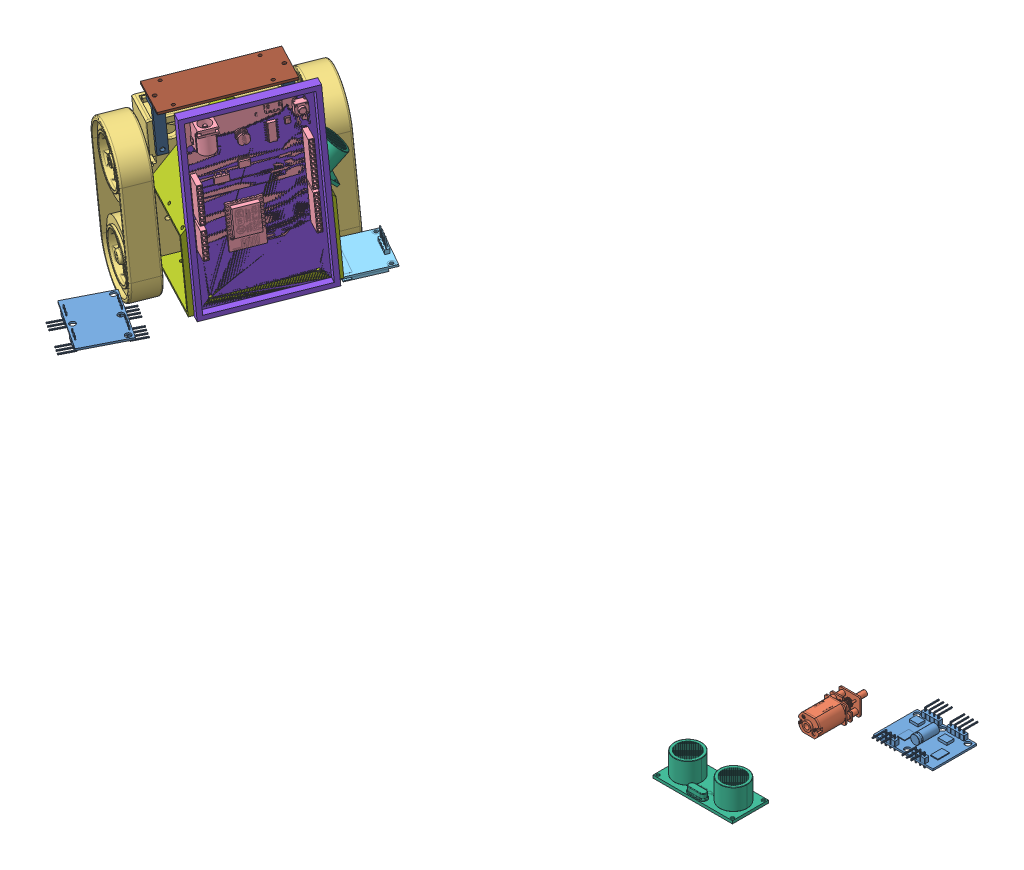
SolidWorks assembly ENGR122_Project, configuration Default. Lengths in mm.
Overall size (434.37 208.02 155.91).
15 component instances, 11 part files, 25 mates.
Components (placement in the parent):
- ENGR122_FeeTech-SMC-4CH-1: ENGR122_FeeTech-SMC-4CH [Default] at (-40.4748 33.8724 47.1125) size (34 8 38)
- ENGR122_DCmotorWgear-1: ENGR122_DCmotorWgear [Default] at (-74.293 41.035 64.7504) size (12.04 10 33.4)
- ENGR122_ZumoChassis-1: ENGR122_ZumoChassis [Default] at (-483.3326 204.8387 50.8004) x (0.037202 -0.996773 -0.071124) z (-0.461988 -0.080266 0.883246) size (87.2 39 99)
- ENGR122_WeMosD1-1: ENGR122_WeMosD1 [Default] at (-388.9016 203.5007 122.9705) x (0.037202 -0.996773 -0.071124) z (0.886105 0 0.463484) size (70.96 53.34 14.5)
- ENGR122_OLED_Display-1: ENGR122_OLED_Display [Default] at (-392.5335 112.0503 26.5045) x (-0.870853 0.002571 -0.491536) z (0.037202 -0.996773 -0.071124) size (26.7 27.86 10.85)
- ENGR122_HCSR04-1: ENGR122_HCSR04 [Default] at (-92.8271 8.0658 62.7388) size (45.31 20.38 60.51)
- ENGR122_Body-1: ENGR122_Body [Default] at (-403.7579 159.6083 60.9495) x (-0.037202 0.996773 0.071124) z (0.461988 0.080266 -0.883246) size (76.2 41.91 66.04)
- ENGR122_Hat-4: ENGR122_Hat [Default] at (-372.2641 143.0258 88.4223) x (0.037202 -0.996773 -0.071124) z (-0.461988 -0.080266 0.883246) size (101.6 5.08 60.96)
- ENGR112_ConnectorA-2: ENGR112_ConnectorA [Default] at (-392.5958 91.7918 104.0934) x (0.037202 -0.996773 -0.071124) z (-0.461988 -0.080266 0.883246) size (12.7 8.89 5.08)
- ENGR112_ConnectorA-3: ENGR112_ConnectorA [Default] at (-369.4931 95.8057 59.9249) x (0.037202 -0.996773 -0.071124) z (-0.461988 -0.080266 0.883246) size (12.7 8.89 5.08)
- ENGR122_HCSR04-2: ENGR122_HCSR04 [Default] at (-413.485 165.1149 47.6247) x (0.343228 -0.672012 -0.656196) z (0.886105 0 0.463484) size (45.31 20.38 60.51)
- ENGR112_ConnectorB-2: ENGR112_ConnectorB [Default] at (-391.4138 239.8096 64.4747) x (-0.037202 0.996773 0.071124) z (0.461988 0.080266 -0.883246) size (25.4 8.89 5.08)
- ENGR112_ConnectorB-3: ENGR112_ConnectorB [Default] at (-416.8231 235.395 113.0532) x (-0.037202 0.996773 0.071124) z (0.461988 0.080266 -0.883246) size (25.4 8.89 5.08)
- ENGR122_Front-1: ENGR122_Front [Default] at (-414.0474 189.9129 59.4508) x (0.461988 0.080266 -0.883246) z (0.037202 -0.996773 -0.071124) size (60.07 22.86 1.27)
- ENGR122_FeeTech-SMC-4CH-2: ENGR122_FeeTech-SMC-4CH [Default] at (-415.5041 103.983 145.0533) x (-0.837314 0.007757 -0.546668) z (-0.545456 -0.079891 0.834323) size (34 8 38)
Mates (geometry in assembly coordinates):
- Coincident5: coincident anti-aligned: plane of ENGR122_ZumoChassis-1 through (-426.2035 174.0605 103.8617) normal (0.886105 0 0.463484); plane of ENGR122_Body-1 through (-403.7667 159.8441 60.9663) normal (-0.886105 0 -0.463484)
- Coincident9: coincident: line of ENGR122_ZumoChassis-1 through (-394.627 121.3557 43.4926) axis (-0.037202 0.996773 0.071124); plane of ENGR122_Body-1 through (-357.1525 112.305 62.2714) normal (0.461988 0.080266 -0.883246)
- Coincident19: coincident aligned: circle of ENGR122_Body-1; cylinder of ENGR122_Hat-4 through (-393.3569 114.7934 106.8272) axis (0.886105 0 0.463484) radius 1.016
- Coincident20: coincident anti-aligned: plane of ENGR122_Body-1 through (-387.6622 107.0042 120.601) normal (0.037202 -0.996773 -0.071124); plane of ENGR112_ConnectorA-2 through (-414.1495 107.4858 99.9973) normal (-0.037202 0.996773 0.071124)
- Coincident21: coincident anti-aligned: plane of ENGR122_ZumoChassis-1 through (-426.2035 174.0605 103.8617) normal (0.886105 0 0.463484); plane of ENGR112_ConnectorA-2 through (-422.027 107.4858 95.8769) normal (-0.886105 0 -0.463484)
- Concentric3: concentric aligned: circle of ENGR122_ZumoChassis-1; circle of ENGR112_ConnectorA-2
- Coincident22: coincident anti-aligned: plane of ENGR122_Body-1 through (-387.6622 107.0042 120.601) normal (0.037202 -0.996773 -0.071124); plane of ENGR112_ConnectorA-3 through (-391.0468 111.4997 55.8288) normal (-0.037202 0.996773 0.071124)
- Coincident23: coincident anti-aligned: plane of ENGR122_ZumoChassis-1 through (-426.2035 174.0605 103.8617) normal (0.886105 0 0.463484); plane of ENGR112_ConnectorA-3 through (-398.9243 111.4997 51.7084) normal (-0.886105 0 -0.463484)
- Coincident25: coincident anti-aligned: plane of ENGR122_Body-1 through (-358.678 153.1774 65.1879) normal (0.311467 0.74054 -0.595474); plane of ENGR122_HCSR04-2 through (-377.0137 178.4162 86.9845) normal (-0.311467 -0.74054 0.595474)
- Parallel5: parallel anti-aligned: line of ENGR122_Body-1 through (-375.2422 185.6087 96.8559) axis (-0.886105 0 -0.463484); line of ENGR122_HCSR04-2 through (-393.0014 187.4371 84.0973) axis (0.886105 0 0.463484)
- Concentric9: concentric anti-aligned: circle of ENGR122_Body-1; circle of ENGR122_HCSR04-2
- Concentric10: concentric anti-aligned: cylinder of ENGR122_Body-1 through (-392.4359 120.0585 53.0043) axis (0.037202 -0.996773 -0.071124) radius 1.016; cylinder of ENGR112_ConnectorA-3 through (-392.0296 109.1717 52.2275) axis (-0.037202 0.996773 0.071124) radius 1.016
- Coincident35: coincident aligned: plane of ENGR122_WeMosD1-1 through (-375.3988 172.3823 97.1554) normal (0.886105 0 0.463484); plane of ENGR122_Hat-4 through (-371.1476 143.2615 89.0277) normal (0.886105 0 0.463484)
- Coincident36: coincident anti-aligned: plane of ENGR122_WeMosD1-1 through (-386.4536 137.9095 118.2903) normal (-0.461988 -0.080266 0.883246); plane of ENGR122_Hat-4 through (-388.9774 205.5306 123.1154) normal (0.461988 0.080266 -0.883246)
- Coincident37: coincident anti-aligned: plane of ENGR122_WeMosD1-1 through (-383.2949 206.5179 112.2514) normal (-0.037202 0.996773 0.071124); plane of ENGR122_Hat-4 through (-363.1614 210.0159 73.7596) normal (0.037202 -0.996773 -0.071124)
- Coincident42: coincident anti-aligned: plane of ENGR122_ZumoChassis-1 through (-426.2035 174.0605 103.8617) normal (0.886105 0 0.463484); plane of ENGR112_ConnectorB-2 through (-398.2419 187.5633 50.4037) normal (-0.886105 0 -0.463484)
- Coincident44: coincident anti-aligned: plane of ENGR122_ZumoChassis-1 through (-426.2035 174.0605 103.8617) normal (0.886105 0 0.463484); plane of ENGR112_ConnectorB-3 through (-423.6512 183.1486 98.9823) normal (-0.886105 0 -0.463484)
- Coincident49: coincident anti-aligned: plane of ENGR122_ZumoChassis-1 through (-426.2035 174.0605 103.8617) normal (0.886105 0 0.463484); plane of ENGR112_ConnectorB-2 through (-398.2419 187.5633 50.4037) normal (-0.886105 0 -0.463484)
- Concentric15: concentric anti-aligned: circle of ENGR122_ZumoChassis-1; circle of ENGR112_ConnectorB-2
- Coincident50: coincident anti-aligned: plane of ENGR112_ConnectorB-2 through (-396.4207 190.0951 51.5864) normal (-0.037202 0.996773 0.071124); plane of ENGR122_Front-1 through (-414.0089 188.8827 59.3773) normal (0.037202 -0.996773 -0.071124)
- Coincident52: coincident anti-aligned: line of ENGR112_ConnectorB-2 through (-396.4207 190.0951 51.5864) axis (-0.886105 0 -0.463484); line of ENGR122_Front-1 through (-410.4954 190.0951 44.2245) axis (0.886105 0 0.463484)
- Concentric16: concentric aligned: circle of ENGR122_ZumoChassis-1; circle of ENGR112_ConnectorB-3
- Coincident54: coincident aligned: circle of ENGR122_Body-1; circle of ENGR122_Hat-4
- Coincident58: coincident anti-aligned: plane of ENGR122_Body-1 through (-387.6622 107.0042 120.601) normal (0.037202 -0.996773 -0.071124); plane of ENGR122_FeeTech-SMC-4CH-2 through (-415.5129 104.2187 145.0702) normal (-0.037202 0.996773 0.071124)
- Coincident60: coincident anti-aligned: plane of ENGR122_OLED_Display-1 through (-366.5047 113.1456 45.5991) normal (-0.037202 0.996773 0.071124); plane of ENGR122_Body-1 through (-387.6622 107.0042 120.601) normal (0.037202 -0.996773 -0.071124)
